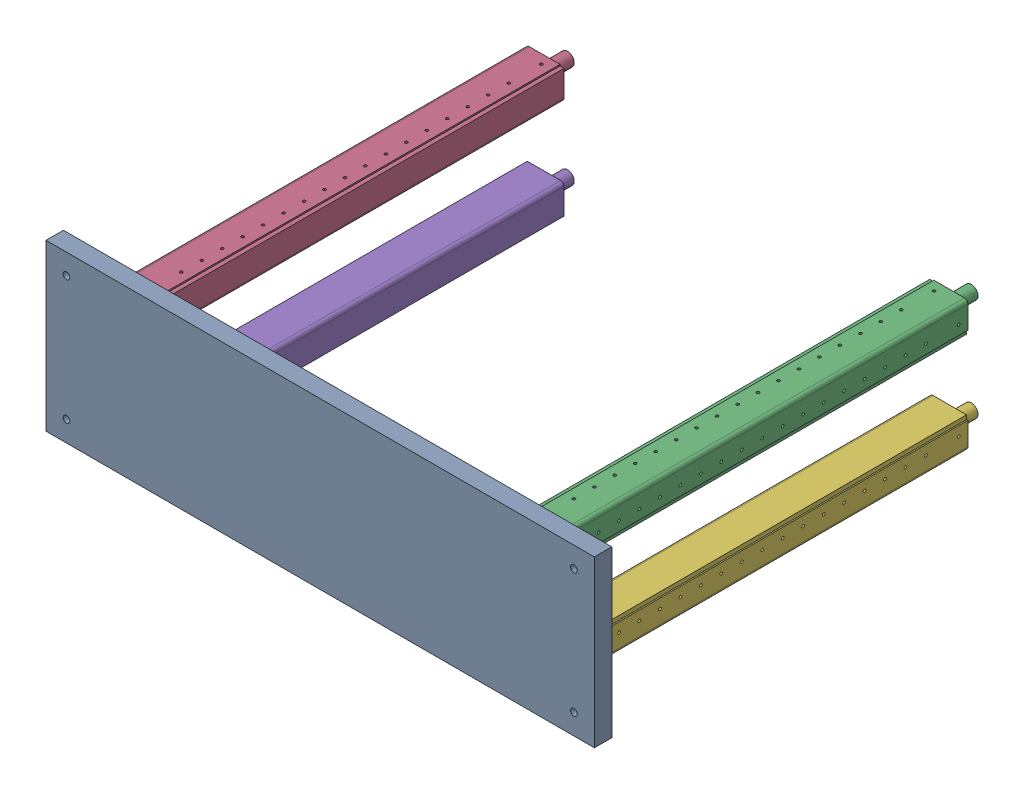
SolidWorks assembly fieldCage, configuration Default. Lengths in mm.
Overall size (402 121.2 329.33).
6 component instances, 4 part files, 0 mates.
Components (placement in the parent):
- FieldCage_Base-1: FieldCage_Base [Default] at (-19.1849 1.3046 -5) size (402 121.2 12.8)
- FieldCage_Cathode-1: FieldCage_Cathode [Default] at (-19.1849 1.3046 -5) x (1 0 0) z (0 0 -1) size (344 113.2 0.03)
- FieldCage_Pillar-1: FieldCage_Pillar [Default] at (128.8151 38.9046 -305.035) size (28 22.3 322.8)
- FieldCage_Pillar_1-1: FieldCage_Pillar_1 [Default] at (-167.1849 38.9046 -305.035) x (0 1 0) z (0 0 1) size (22.3 28 322.8)
- FieldCage_Pillar-2: FieldCage_Pillar [Default] at (-167.1849 -36.2954 -305.035) x (-1 0 0) z (0 0 1) size (28 22.3 322.8)
- FieldCage_Pillar_1-2: FieldCage_Pillar_1 [Default] at (128.8151 -36.2954 -305.035) x (0 -1 0) z (0 0 1) size (22.3 28 322.8)
